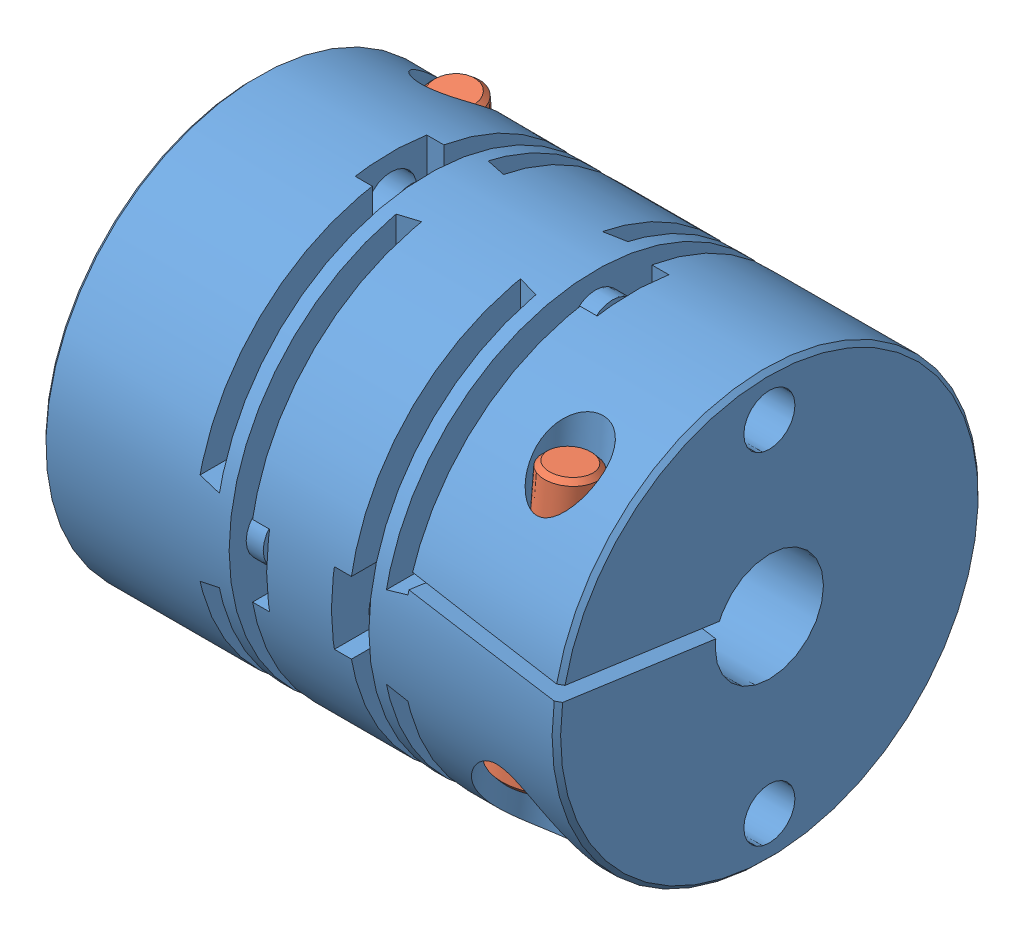
SolidWorks assembly MCSLC25_6_35_6_35, configuration Default. Lengths in mm.
Overall size (30.2 25 25).
3 component instances, 2 part files, 0 mates.
Components (placement in the parent):
- Dummy_MCSLC25_6_35_6_35-1: Dummy_MCSLC25_6_35_6_35 [Default] at origin size (30.2 25 25)
- M3x12-1: M3x12 [Default] at (4 -2.2478 -8.7291) x (0 0.996195 0.087156) z (0 -0.087156 0.996195) size (14.86 5.5 5.5)
- M3x12-2: M3x12 [Default] at (26.2 -2.2478 8.7291) x (0 0.996195 -0.087156) z (-1 0 0) size (14.86 5.5 5.5)
